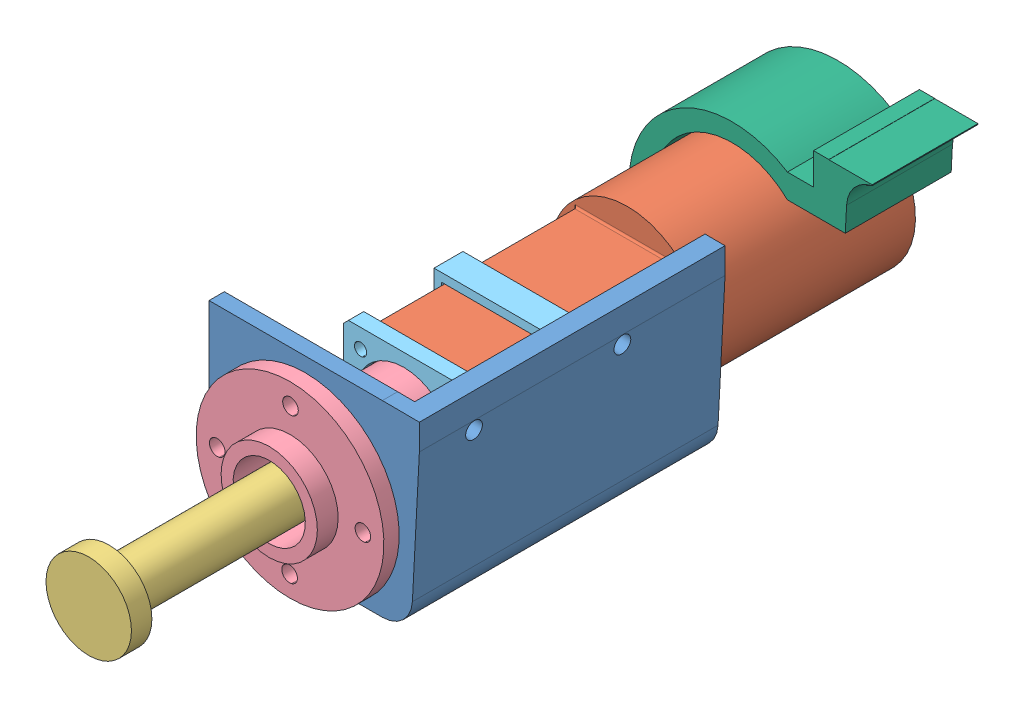
SolidWorks assembly assemblage moteur_simplifie-braquette-sol_sansPlancher, configuration Default. Lengths in mm.
Overall size (163.91 86.22 311.5).
7 component instances, 6 part files, 7 mates.
Components (placement in the parent):
- braquette bleu-1: braquette bleu [Default] at (-188.5719 315.838 826.9542) x (0 0 -1) z (1 0 0) size (205.75 78 138.28)
- D-01-04-1: D-01-04 [Default] at (-199.7546 211.4142 762.3925) x (0 0 1) z (0 1 0) size (311.5 78.45 78.45)
  - moteur_pla_simplifie-2: moteur_pla_simplifie [Default] at (-156.9384 51.1827 137.4238) size (176.5 64 64)
  - moteur_axe_pla_simplifie-1: moteur_axe_pla_simplifie [Default] at (3.5616 51.1827 137.4238) size (151 35.5 35.5)
  - front_housing_moteur_pla_simplifie-2: front_housing_moteur_pla_simplifie [Default] at (64.5616 51.1827 137.4238) x (1 0 0) z (0 0.00581 0.999983) size (60 78 78)
- braquette gearbox-1: braquette gearbox [Default] at (-173.6322 327.188 785.9741) x (-0.000012 0 -1) z (0 -1 0) size (72.34 80.66 66.5)
- D-01-01-1: D-01-01 [Default] at (-148.5686 348.838 605.4542) x (-1 0 0) z (0 0 -1) size (123.62 80 44)
Mates (geometry in assembly coordinates):
- Concentric1: concentric aligned: circle of braquette bleu-1; circle of assemblage_moteur_pla_simplifie-1/front_housing_moteur_pla_simplifie-2
- Parallel2: parallel anti-aligned: plane of braquette bleu-1 through (-108.5719 322.188 659.9542) normal (0 1 0); plane of assemblage_moteur_pla_simplifie-1/moteur_pla_simplifie-2 through (-127.5719 327.838 781.9542) normal (0 -1 0)
- Coincident9: coincident anti-aligned: plane of braquette bleu-1 through (-108.5719 322.188 659.9542) normal (0 1 0); plane of braquette gearbox-1 through (-173.6322 322.188 785.9741) normal (0 -1 0)
- Concentric17: concentric aligned: circle of braquette bleu-1; circle of braquette gearbox-1
- Coincident19: coincident anti-aligned: plane of braquette bleu-1 through (-108.5719 315.838 826.9542) normal (0 0 1); plane of assemblage_moteur_pla_simplifie-1/front_housing_moteur_pla_simplifie-2 through (-148.5719 348.838 826.9542) normal (0 0 -1)
- Coincident23: coincident aligned: plane of assemblage_moteur_pla_simplifie-1/moteur_pla_simplifie-2 through (-148.5719 348.838 605.4542) normal (0 0 -1); plane of braquette moteur- v2-1 through (-148.699 346.4685 605.4542) normal (0 0 -1)
- Concentric22: concentric aligned: cylinder of assemblage_moteur_pla_simplifie-1/moteur_pla_simplifie-2 through (-148.5719 348.838 693.1742) axis (0 0 -1) radius 32; cylinder of braquette moteur- v2-1 through (-148.5719 348.838 649.4542) axis (0 0 -1) radius 33
